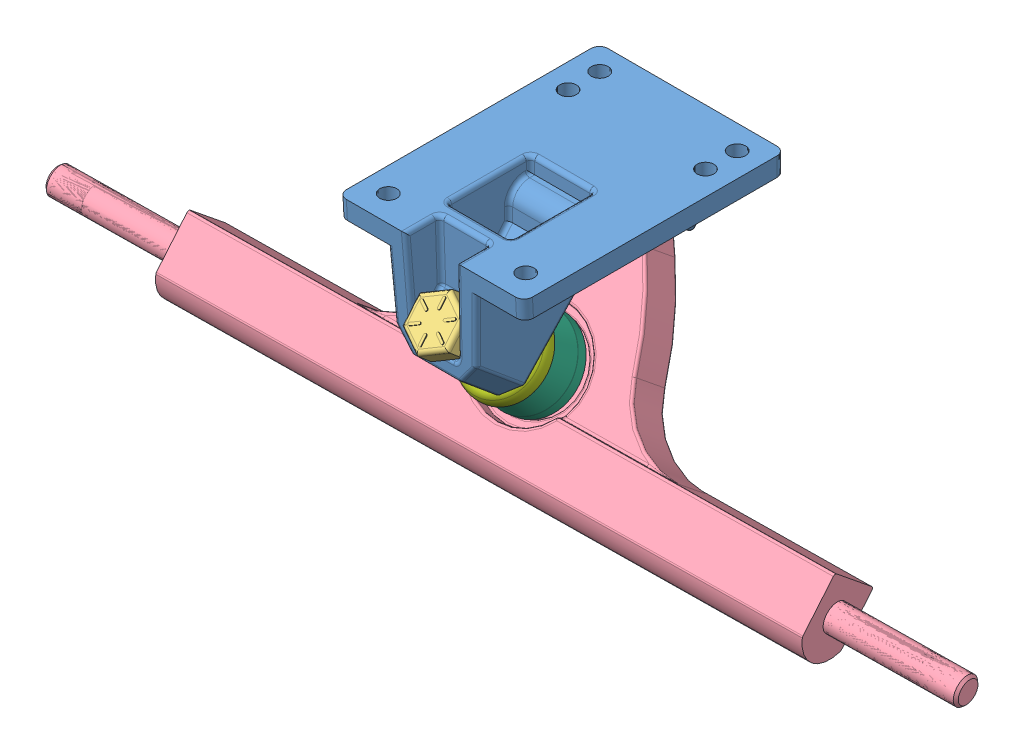
SolidWorks assembly Truck Assy, configuration Standard. Lengths in mm.
Overall size (254.41 91.3 91.66).
9 component instances, 9 part files, 22 mates.
Components (placement in the parent):
- Caliber 50deg Baseplate-1: Caliber 50deg Baseplate [Default] x (-1 0 0) z (0 0 1) size (55.88 41.6 78.53)
- Pivot Cup-1: Pivot Cup [Default] at (0 -17.9932 -20.9048) x (-0.857791 -0.330391 -0.393745) z (-0.513998 0.551378 0.657106) size (17.46 19.05 17.46)
- Kingpin-1: Kingpin [Default] at (0 -23.4623 34.0838) x (0 -0.766044 0.642788) z (-1 0 0) size (16.06 70.1 13.91)
- Caliber Hanger-1: Caliber Hanger [Default] at (0 -54.0678 9.3654) x (-0.993856 0.071145 0.084787) z (0.110681 0.638838 0.761338) size (254 80.77 17.78)
- BS Bushing-1: BS Bushing [Default] at (0 -59.0778 -8.3611) x (0.969006 0.189241 -0.158792) z (0.247036 -0.742302 0.622865) size (24.64 14.73 24.64)
- RS Bushing-1: RS Bushing [Default] at (0 -45.7515 7.5206) x (-0.938473 0.264556 -0.221989) z (0.345354 0.718912 -0.603239) size (24.77 14.61 24.77)
- RS Washer-1: RS Washer [Default] at (0 -35.384 19.8761) x (0.240142 -0.743628 0.623978) z (0.970738 0.18396 -0.15436) size (24.51 4.01 24.51)
- BS Washer-1: BS Washer [Default] at (0 -60.0574 -9.5285) x (0.994852 -0.07763 0.065139) z (-0.101338 -0.762101 0.639479) size (29.08 4.06 29.08)
- Kingpin Nut-1: Kingpin Nut [90630A115] at (0 -60.0574 -9.5285) x (-0.999554 0.022877 -0.019196) z (-0.029863 -0.765703 0.642501) size (12.7 8.97 14.66)
Mates (geometry in assembly coordinates):
- Deckungsgleich1: coincident aligned: plane of Caliber 50deg Baseplate-1 through (0 0 0) normal (0 1 0)
- Parallel1: parallel aligned: plane of Caliber 50deg Baseplate-1 through (27.94 -5.6388 39.116) normal (1 0 0)
- Deckungsgleich4: coincident: point of Caliber 50deg Baseplate-1
- Deckungsgleich5: coincident: unknown of Caliber 50deg Baseplate-1
- Konzentrisch1: concentric anti-aligned: cylinder of Caliber 50deg Baseplate-1 through (0 -2.2326 -34.1295) axis (0 0.766044 -0.642788) radius 8.89; cylinder of Pivot Cup-1 through (0 -7.4861 -29.7212) axis (0 -0.766044 0.642788) radius 8.7312
- Deckungsgleich6: coincident aligned: plane of Caliber 50deg Baseplate-1 through (27.94 -9.8298 -11.176) normal (0 -0.766044 0.642788); plane of Pivot Cup-1 through (-5.447 -20.0912 -23.405) normal (0 -0.766044 0.642788)
- Konzentrisch3: concentric aligned: cylinder of Caliber 50deg Baseplate-1 through (0 -66.9996 -17.8019) axis (0 0.642788 0.766044) radius 4.7307; cylinder of Kingpin-1 through (0 -64.2793 -14.56) axis (0 0.642788 0.766044) radius 4.6609
- Parallel5: parallel aligned: plane of Kingpin-1 through (-6.9533 -16.3053 36.3677) normal (-1 0 0); plane of Caliber 50deg Baseplate-1 through (-27.94 -5.6388 39.116) normal (-1 0 0)
- Deckungsgleich10: coincident anti-aligned: plane of Caliber 50deg Baseplate-1 through (7.62 -17.7034 29.2515) normal (0 0.642788 0.766044); plane of Kingpin-1 through (0 -23.4623 34.0838) normal (0 -0.642788 -0.766044)
- Konzentrisch4: concentric aligned: cylinder of Pivot Cup-1 through (0 -7.4861 -29.7212) axis (0 -0.766044 0.642788) radius 6.35; cylinder of Caliber Hanger-1 through (0 -17.5849 -21.2473) axis (0 -0.766044 0.642788) radius 6.35
- Deckungsgleich11: coincident: line of Kingpin-1 through (0 -63.7895 -13.9763) axis (0 0.642788 0.766044); unknown of Caliber Hanger-1
- Konzentrisch5: concentric anti-aligned: cylinder of Kingpin-1 through (0 -64.2793 -14.56) axis (0 0.642788 0.766044) radius 4.6609; cylinder of BS Bushing-1 through (0 -49.6082 2.9243) axis (0 -0.642788 -0.766044) radius 4.7625
- Konzentrisch6: concentric aligned: cylinder of Kingpin-1 through (0 -64.2793 -14.56) axis (0 0.642788 0.766044) radius 4.6609; cylinder of RS Washer-1 through (0 -35.384 19.8761) axis (0 0.642788 0.766044) radius 5.0165
- Deckungsgleich12: coincident anti-aligned: plane of Caliber 50deg Baseplate-1 through (27.94 -13.5128 1.524) normal (0 -0.642788 -0.766044); plane of RS Washer-1 through (1.2047 -39.1144 23.0063) normal (0 0.642788 0.766044)
- Konzentrisch7: concentric anti-aligned: cylinder of Kingpin-1 through (0 -64.2793 -14.56) axis (0 0.642788 0.766044) radius 4.6609; cylinder of RS Bushing-1 through (0 -45.7515 7.5206) axis (0 -0.642788 -0.766044) radius 4.7625
- Deckungsgleich14: coincident anti-aligned: plane of RS Bushing-1 through (-4.9462 -34.9692 17.5387) normal (0 0.642788 0.766044); plane of RS Washer-1 through (1.2047 -40.094 21.8388) normal (0 -0.642788 -0.766044)
- Deckungsgleich15: coincident anti-aligned: plane of Caliber Hanger-1; plane of BS Bushing-1 through (0 -49.6017 2.9321) normal (0 0.642788 0.766044)
- Deckungsgleich16: coincident anti-aligned: plane of BS Bushing-1 through (0 -59.0778 -8.3611) normal (0 -0.642788 -0.766044); plane of BS Washer-1 through (4.738 -59.4475 -8.0508) normal (0 0.642788 0.766044)
- Konzentrisch8: concentric anti-aligned: cylinder of Kingpin-1 through (0 -64.2793 -14.56) axis (0 0.642788 0.766044) radius 4.6609; cylinder of BS Washer-1 through (0 -60.0574 -9.5285) axis (0 -0.642788 -0.766044) radius 4.7625
- Deckungsgleich19: coincident anti-aligned: plane of BS Washer-1 through (4.738 -60.4271 -9.2183) normal (0 -0.642788 -0.766044); plane of Kingpin Nut-1 through (-6.2377 -57.1049 -12.0059) normal (0 0.642788 0.766044)
- Abstand1: distance = 6 mm anti-aligned: plane of RS Bushing-1 through (-11.6206 -42.4756 4.7718) normal (0 -0.642788 -0.766044); plane of BS Bushing-1 through (0 -49.6082 2.9243) normal (0 0.642788 0.766044)
- Konzentrisch9: concentric aligned: cylinder of Kingpin-1 through (0 -64.2793 -14.56) axis (0 0.642788 0.766044) radius 4.6609; cylinder of Kingpin Nut-1 through (0 -64.7833 -15.1607) axis (0 0.642788 0.766044) radius 3.3248
